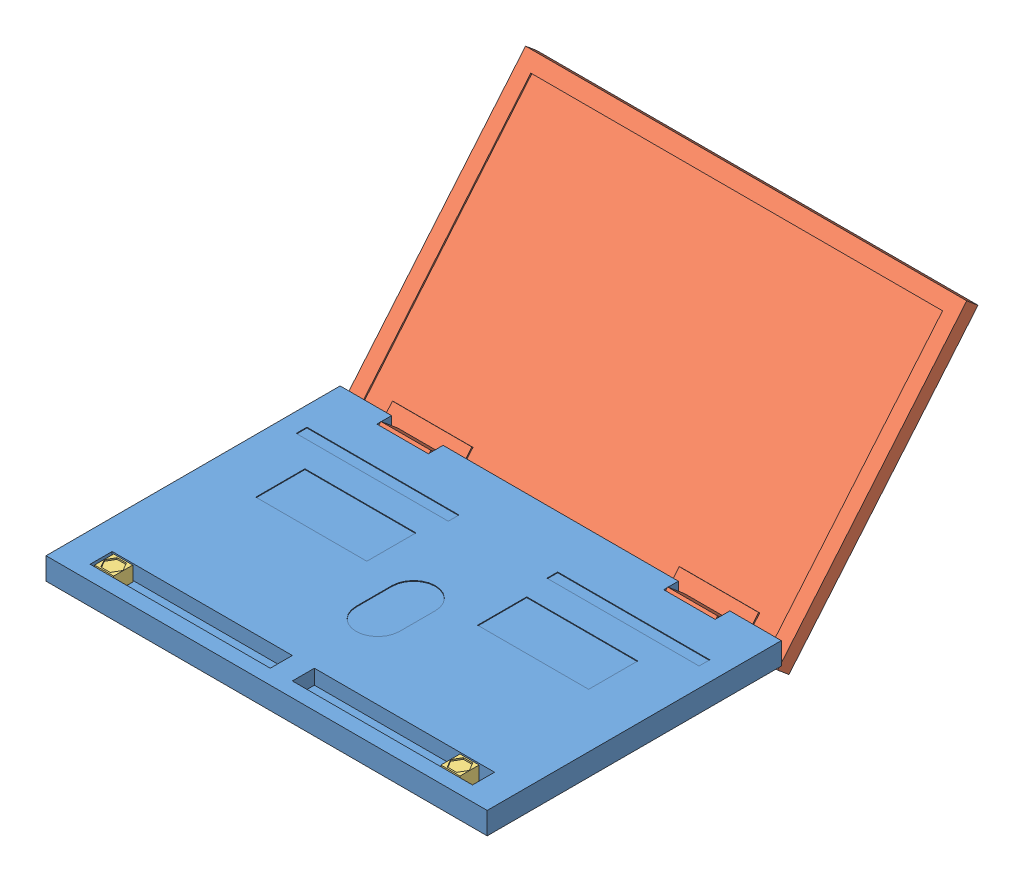
SolidWorks assembly lec35-distance-angle-ranges, configuration Default. Lengths in mm.
Overall size (300 169.28 333.75).
4 component instances, 3 part files, 17 mates.
Components (placement in the parent):
- Keyboard^lec35-distance-angle-ranges-1: Keyboard^lec35-distance-angle-ranges [Default] at origin size (300 15 200) (virtual)
- screen^lec35-distance-angle-ranges-1: screen^lec35-distance-angle-ranges [Default] at (0 75.4533 -161.8102) x (1 0 0) z (0 -0.642788 -0.766044) size (300 200 25) (virtual)
- Key^lec35-distance-angle-ranges-1: Key^lec35-distance-angle-ranges [Default] at (37.6688 5 87.5294) x (1 0 0) z (0 1 0) size (13 13 10) (virtual)
- Key^lec35-distance-angle-ranges-2: Key^lec35-distance-angle-ranges [Default] at (-197.8312 5 87.5294) x (1 0 0) z (0 1 0) size (13 13 10) (virtual)
Mates (geometry in assembly coordinates):
- InPlace1: in place: plane of Keyboard^lec35-distance-angle-ranges-1 through (0 15 0) normal (0 1 0); plane of ? through (0 15 0) normal (0 1 0); moOrthogonalPlaneRef_w of Keyboard^lec35-distance-angle-ranges-1 through (0 15 0) normal (0 1 0); plane of ? through (0 15 0) normal (0 0 -1); plane of Keyboard^lec35-distance-angle-ranges-1 through (0 15 0) normal (0 1 0); line of ? through (-55 0 15) axis (0 1 0); plane of Keyboard^lec35-distance-angle-ranges-1 through (0 15 0) normal (0 1 0); unknown of ?
- Coincident1: coincident aligned: plane of ?; plane of ?
- Coincident2: coincident aligned: moOrthogonalPlaneRef_w of Keyboard^lec35-distance-angle-ranges-1 through (0 15 0) normal (0 0 -1); plane of screen^lec35-distance-angle-ranges-1
- Coincident3: coincident anti-aligned: moOrthogonalPlaneRef_w of Keyboard^lec35-distance-angle-ranges-1 through (0 15 0) normal (-1 0 0); plane of screen^lec35-distance-angle-ranges-1 through (0 72.8263 -164.381) normal (1 0 0)
- InPlace2: in place: plane of Keyboard^lec35-distance-angle-ranges-1 through (0 5 0) normal (0 1 0); plane of ? through (0 5 0) normal (0 1 0); plane of Keyboard^lec35-distance-angle-ranges-1 through (0 5 0) normal (0 1 0); plane of ? through (0 5 0) normal (0 0 -1); plane of Keyboard^lec35-distance-angle-ranges-1 through (0 5 0) normal (0 1 0); line of ? through (-55 0 5) axis (0 1 0); plane of Keyboard^lec35-distance-angle-ranges-1 through (0 5 0) normal (0 1 0); unknown of ?
- Coincident4: coincident aligned: plane of ?; plane of ?
- Coincident5: coincident aligned: moOrthogonalPlaneRef_w of Keyboard^lec35-distance-angle-ranges-1 through (0 5 0) normal (0 0 -1); plane of Key^lec35-distance-angle-ranges-1 through (-40.7227 5 87.5294) normal (0 0 -1)
- Coincident6: coincident anti-aligned: moOrthogonalPlaneRef_w of Keyboard^lec35-distance-angle-ranges-1 through (0 5 0) normal (-1 0 0); plane of Key^lec35-distance-angle-ranges-1 through (-40.7227 5 87.5294) normal (1 0 0)
- Coincident8: coincident anti-aligned: plane of Keyboard^lec35-distance-angle-ranges-1 through (0 5 0) normal (0 1 0); plane of Key^lec35-distance-angle-ranges-1 through (37.6688 5 87.5294) normal (0 -1 0)
- Width1: width anti-aligned: plane of Key^lec35-distance-angle-ranges-1 through (120.5 15 89) normal (0 0 1); plane of Keyboard^lec35-distance-angle-ranges-1 through (120.5 15 76) normal (0 0 -1); plane of Key^lec35-distance-angle-ranges-1 through (0 5 90) normal (0 0 -1); plane of Keyboard^lec35-distance-angle-ranges-1 through (0 5 75) normal (0 0 1)
- Concentric1: concentric aligned: cylinder of Keyboard^lec35-distance-angle-ranges-1 through (-150 7.5 -95) axis (1 0 0) radius 3; cylinder of screen^lec35-distance-angle-ranges-1 through (-150 7.5 -95) axis (1 0 0) radius 3
- Coincident9: coincident aligned: plane of Keyboard^lec35-distance-angle-ranges-1 through (150 15 -100) normal (1 0 0); plane of screen^lec35-distance-angle-ranges-1 through (150 -7.579 -105.1918) normal (1 0 0)
- Coincident11: coincident anti-aligned: plane of Keyboard^lec35-distance-angle-ranges-1 through (0 5 0) normal (0 1 0); plane of Key^lec35-distance-angle-ranges-2 through (-197.8312 5 87.5294) normal (0 -1 0)
- Width2: width anti-aligned: plane of Key^lec35-distance-angle-ranges-2 through (-115 15 89) normal (0 0 1); plane of Keyboard^lec35-distance-angle-ranges-1 through (-115 15 76) normal (0 0 -1); plane of Key^lec35-distance-angle-ranges-2 through (0 5 90) normal (0 0 -1); plane of Keyboard^lec35-distance-angle-ranges-1 through (0 5 75) normal (0 0 1)
- LimitAngle1: limit planar angle = 2.268928 rad anti-aligned: plane of screen^lec35-distance-angle-ranges-1 through (0 75.4533 -161.8102) normal (0 0.642788 0.766044); plane of Keyboard^lec35-distance-angle-ranges-1 through (0 15 0) normal (0 1 0)
- LimitDistance1: limit distance = 2 mm anti-aligned: plane of Keyboard^lec35-distance-angle-ranges-1 through (-130 5 0) normal (1 0 0); plane of Key^lec35-distance-angle-ranges-2 through (-128 15 89) normal (-1 0 0)
- LimitDistance2: limit distance = 100 mm anti-aligned: plane of Key^lec35-distance-angle-ranges-1 through (107.5 15 89) normal (-1 0 0); plane of Keyboard^lec35-distance-angle-ranges-1 through (7.5 5 0) normal (1 0 0)
